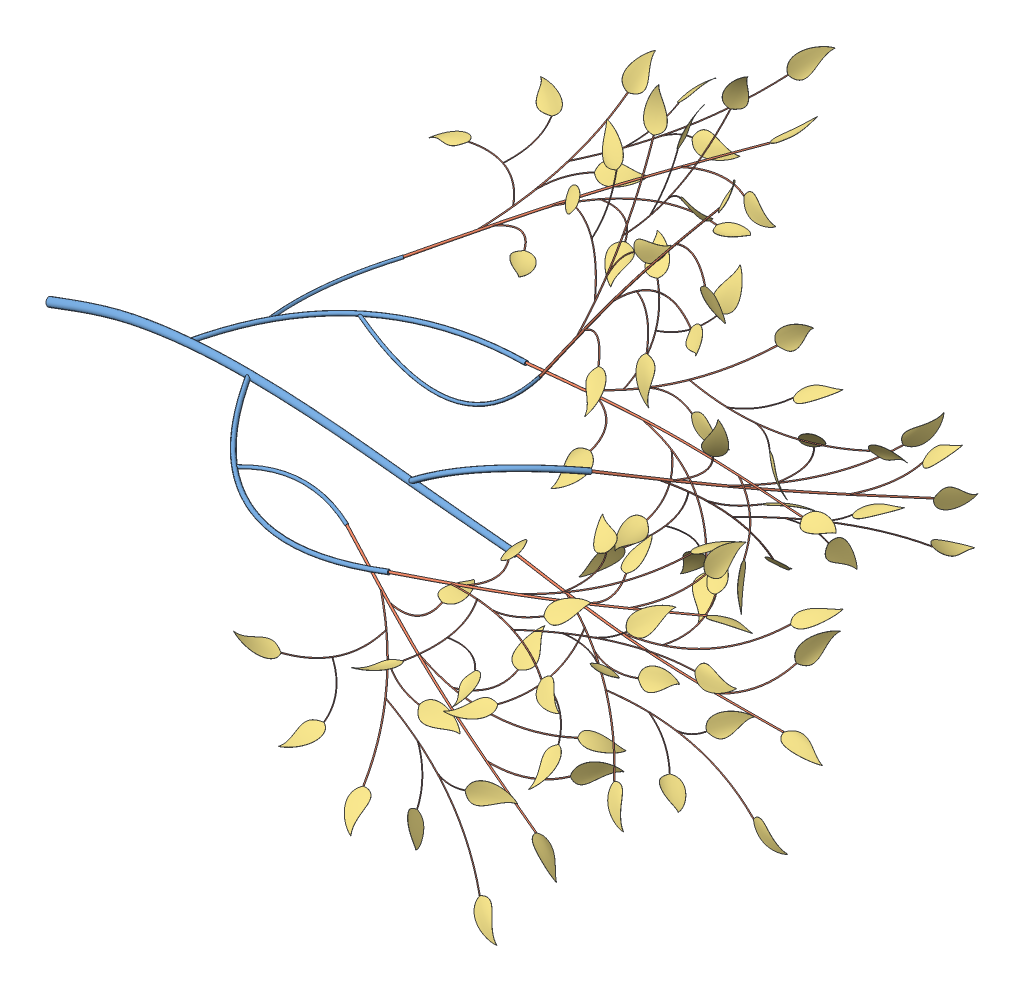
SolidWorks assembly Medium Branch, configuration Default. Lengths in mm.
Overall size (1047.38 776.48 982.97).
99 component instances, 3 part files, 14 mates.
Components (placement in the parent):
- Medium Branch-1: Medium Branch [Default] at origin size (606.89 129.86 395)
- Small Branch-1: Small Branch [Default] at (234.8483 58.1429 -218.8325) x (0.850592 -0.059738 0.522421) z (-0.522421 -0.208881 0.826707) size (314.27 42.14 439.71)
  - Small Branch-1: Small Branch [Default] at origin size (214.34 2.87 387.61)
  - Leaf-1: Leaf [Default] at (-126.8501 0 -93.2963) x (-0.636908 -0.142761 -0.757607) z (0.709104 0.277141 -0.648355) size (26.78 6 52.05)
  - Leaf-2: Leaf [Default] at (-126.8501 0 -172.3953) x (-0.013277 -0.285636 -0.958246) z (0.991939 -0.124542 0.02338) size (26.78 6 52.05)
  - Leaf-3: Leaf [Default] at (-126.8501 0 -245.0718) x (-0.525154 0.599129 0.604365) z (0.614609 -0.22419 0.756303) size (26.78 6 52.05)
  - Leaf-4: Leaf [Default] at (-92.3172 0 -285.5855) x (0.533069 0.650396 -0.54113) z (0.556089 0.212694 0.803447) size (26.78 6 52.05)
  - Leaf-5: Leaf [Default] at (-84.2583 0 -387.3824) x (-0.420387 0.890967 0.171619) z (0.131866 -0.127143 0.98308) size (26.78 6 52.05)
  - Leaf-6: Leaf [Default] at (-40.2332 0 -285.5855) x (0.372303 -0.768109 0.520961) z (-0.655996 0.179296 0.73316) size (26.78 6 52.05)
  - Leaf-7: Leaf [Default] at (-34.0505 0 -190.6428) x (0.783569 -0.523086 0.335262) z (-0.242974 0.238646 0.940219) size (26.78 6 52.05)
  - Leaf-8: Leaf [Default] at (-0.8972 0 -350) x (-0.8697 -0.488533 -0.070406) z (0.058885 -0.244321 0.967905) size (26.78 6 52.05)
  - Leaf-9: Leaf [Default] at (59.3764 0 -310.8062) x (0.063601 -0.898301 0.434754) z (-0.913477 0.123031 0.387844) size (26.78 6 52.05)
  - Leaf-10: Leaf [Default] at (86.7887 0 -277.9973) x (-0.409978 -0.23426 -0.881499) z (-0.842796 -0.272218 0.46432) size (26.78 6 52.05)
  - Leaf-11: Leaf [Default] at (71.4865 0 -194.3436) x (-0.415399 0.323221 0.850278) z (-0.822836 0.264979 -0.50272) size (26.78 6 52.05)
  - Leaf-12: Leaf [Default] at (41.4889 0 -105.4654) x (0.385119 -0.368279 -0.8462) z (-0.916478 -0.260329 -0.303804) size (26.78 6 52.05)
- Small Branch-2: Small Branch [Default] at (421.3694 47.2127 -190.7732) x (0.008005 -0.804807 0.593482) z (-0.999909 0 0.013487) size (314.27 42.14 439.71)
  - Small Branch-1: Small Branch [Default] at origin size (214.34 2.87 387.61)
  - Leaf-1: Leaf [Default] at (-126.8501 0 -93.2963) x (-0.636908 -0.142761 -0.757607) z (0.709104 0.277141 -0.648355) size (26.78 6 52.05)
  - Leaf-2: Leaf [Default] at (-126.8501 0 -172.3953) x (-0.013277 -0.285636 -0.958246) z (0.991939 -0.124542 0.02338) size (26.78 6 52.05)
  - Leaf-3: Leaf [Default] at (-126.8501 0 -245.0718) x (-0.525154 0.599129 0.604365) z (0.614609 -0.22419 0.756303) size (26.78 6 52.05)
  - Leaf-4: Leaf [Default] at (-92.3172 0 -285.5855) x (0.533069 0.650396 -0.54113) z (0.556089 0.212694 0.803447) size (26.78 6 52.05)
  - Leaf-5: Leaf [Default] at (-84.2583 0 -387.3824) x (-0.420387 0.890967 0.171619) z (0.131866 -0.127143 0.98308) size (26.78 6 52.05)
  - Leaf-6: Leaf [Default] at (-40.2332 0 -285.5855) x (0.372303 -0.768109 0.520961) z (-0.655996 0.179296 0.73316) size (26.78 6 52.05)
  - Leaf-7: Leaf [Default] at (-34.0505 0 -190.6428) x (0.783569 -0.523086 0.335262) z (-0.242974 0.238646 0.940219) size (26.78 6 52.05)
  - Leaf-8: Leaf [Default] at (-0.8972 0 -350) x (-0.8697 -0.488533 -0.070406) z (0.058885 -0.244321 0.967905) size (26.78 6 52.05)
  - Leaf-9: Leaf [Default] at (59.3764 0 -310.8062) x (0.063601 -0.898301 0.434754) z (-0.913477 0.123031 0.387844) size (26.78 6 52.05)
  - Leaf-10: Leaf [Default] at (86.7887 0 -277.9973) x (-0.409978 -0.23426 -0.881499) z (-0.842796 -0.272218 0.46432) size (26.78 6 52.05)
  - Leaf-11: Leaf [Default] at (71.4865 0 -194.3436) x (-0.415399 0.323221 0.850278) z (-0.822836 0.264979 -0.50272) size (26.78 6 52.05)
  - Leaf-12: Leaf [Default] at (41.4889 0 -105.4654) x (0.385119 -0.368279 -0.8462) z (-0.916478 -0.260329 -0.303804) size (26.78 6 52.05)
- Small Branch-3: Small Branch [Default] at (521.8164 123.8657 -108.6707) x (0.683067 -0.468153 0.560582) z (-0.597406 -0.799683 0.060107) size (314.27 42.14 439.71)
  - Small Branch-1: Small Branch [Default] at origin size (214.34 2.87 387.61)
  - Leaf-1: Leaf [Default] at (-126.8501 0 -93.2963) x (-0.636908 -0.142761 -0.757607) z (0.709104 0.277141 -0.648355) size (26.78 6 52.05)
  - Leaf-2: Leaf [Default] at (-126.8501 0 -172.3953) x (-0.013277 -0.285636 -0.958246) z (0.991939 -0.124542 0.02338) size (26.78 6 52.05)
  - Leaf-3: Leaf [Default] at (-126.8501 0 -245.0718) x (-0.525154 0.599129 0.604365) z (0.614609 -0.22419 0.756303) size (26.78 6 52.05)
  - Leaf-4: Leaf [Default] at (-92.3172 0 -285.5855) x (0.533069 0.650396 -0.54113) z (0.556089 0.212694 0.803447) size (26.78 6 52.05)
  - Leaf-5: Leaf [Default] at (-84.2583 0 -387.3824) x (-0.420387 0.890967 0.171619) z (0.131866 -0.127143 0.98308) size (26.78 6 52.05)
  - Leaf-6: Leaf [Default] at (-40.2332 0 -285.5855) x (0.372303 -0.768109 0.520961) z (-0.655996 0.179296 0.73316) size (26.78 6 52.05)
  - Leaf-7: Leaf [Default] at (-34.0505 0 -190.6428) x (0.783569 -0.523086 0.335262) z (-0.242974 0.238646 0.940219) size (26.78 6 52.05)
  - Leaf-8: Leaf [Default] at (-0.8972 0 -350) x (-0.8697 -0.488533 -0.070406) z (0.058885 -0.244321 0.967905) size (26.78 6 52.05)
  - Leaf-9: Leaf [Default] at (59.3764 0 -310.8062) x (0.063601 -0.898301 0.434754) z (-0.913477 0.123031 0.387844) size (26.78 6 52.05)
  - Leaf-10: Leaf [Default] at (86.7887 0 -277.9973) x (-0.409978 -0.23426 -0.881499) z (-0.842796 -0.272218 0.46432) size (26.78 6 52.05)
  - Leaf-11: Leaf [Default] at (71.4865 0 -194.3436) x (-0.415399 0.323221 0.850278) z (-0.822836 0.264979 -0.50272) size (26.78 6 52.05)
  - Leaf-12: Leaf [Default] at (41.4889 0 -105.4654) x (0.385119 -0.368279 -0.8462) z (-0.916478 -0.260329 -0.303804) size (26.78 6 52.05)
- Small Branch-4: Small Branch [Default] at (601.2333 65.1322 -93.4934) x (0.532435 0.844514 -0.05753) z (-0.403263 0.312824 0.859954) size (314.27 42.14 439.71)
  - Small Branch-1: Small Branch [Default] at origin size (214.34 2.87 387.61)
  - Leaf-1: Leaf [Default] at (-126.8501 0 -93.2963) x (-0.636908 -0.142761 -0.757607) z (0.709104 0.277141 -0.648355) size (26.78 6 52.05)
  - Leaf-2: Leaf [Default] at (-126.8501 0 -172.3953) x (-0.013277 -0.285636 -0.958246) z (0.991939 -0.124542 0.02338) size (26.78 6 52.05)
  - Leaf-3: Leaf [Default] at (-126.8501 0 -245.0718) x (-0.525154 0.599129 0.604365) z (0.614609 -0.22419 0.756303) size (26.78 6 52.05)
  - Leaf-4: Leaf [Default] at (-92.3172 0 -285.5855) x (0.533069 0.650396 -0.54113) z (0.556089 0.212694 0.803447) size (26.78 6 52.05)
  - Leaf-5: Leaf [Default] at (-84.2583 0 -387.3824) x (-0.420387 0.890967 0.171619) z (0.131866 -0.127143 0.98308) size (26.78 6 52.05)
  - Leaf-6: Leaf [Default] at (-40.2332 0 -285.5855) x (0.372303 -0.768109 0.520961) z (-0.655996 0.179296 0.73316) size (26.78 6 52.05)
  - Leaf-7: Leaf [Default] at (-34.0505 0 -190.6428) x (0.783569 -0.523086 0.335262) z (-0.242974 0.238646 0.940219) size (26.78 6 52.05)
  - Leaf-8: Leaf [Default] at (-0.8972 0 -350) x (-0.8697 -0.488533 -0.070406) z (0.058885 -0.244321 0.967905) size (26.78 6 52.05)
  - Leaf-9: Leaf [Default] at (59.3764 0 -310.8062) x (0.063601 -0.898301 0.434754) z (-0.913477 0.123031 0.387844) size (26.78 6 52.05)
  - Leaf-10: Leaf [Default] at (86.7887 0 -277.9973) x (-0.409978 -0.23426 -0.881499) z (-0.842796 -0.272218 0.46432) size (26.78 6 52.05)
  - Leaf-11: Leaf [Default] at (71.4865 0 -194.3436) x (-0.415399 0.323221 0.850278) z (-0.822836 0.264979 -0.50272) size (26.78 6 52.05)
  - Leaf-12: Leaf [Default] at (41.4889 0 -105.4654) x (0.385119 -0.368279 -0.8462) z (-0.916478 -0.260329 -0.303804) size (26.78 6 52.05)
- Small Branch-5: Small Branch [Default] at (599.6756 19.6986 1.0621) x (0.039468 0.490905 -0.870319) z (-0.998014 0.062159 -0.010198) size (314.27 42.14 439.71)
  - Small Branch-1: Small Branch [Default] at origin size (214.34 2.87 387.61)
  - Leaf-1: Leaf [Default] at (-126.8501 0 -93.2963) x (-0.636908 -0.142761 -0.757607) z (0.709104 0.277141 -0.648355) size (26.78 6 52.05)
  - Leaf-2: Leaf [Default] at (-126.8501 0 -172.3953) x (-0.013277 -0.285636 -0.958246) z (0.991939 -0.124542 0.02338) size (26.78 6 52.05)
  - Leaf-3: Leaf [Default] at (-126.8501 0 -245.0718) x (-0.525154 0.599129 0.604365) z (0.614609 -0.22419 0.756303) size (26.78 6 52.05)
  - Leaf-4: Leaf [Default] at (-92.3172 0 -285.5855) x (0.533069 0.650396 -0.54113) z (0.556089 0.212694 0.803447) size (26.78 6 52.05)
  - Leaf-5: Leaf [Default] at (-84.2583 0 -387.3824) x (-0.420387 0.890967 0.171619) z (0.131866 -0.127143 0.98308) size (26.78 6 52.05)
  - Leaf-6: Leaf [Default] at (-40.2332 0 -285.5855) x (0.372303 -0.768109 0.520961) z (-0.655996 0.179296 0.73316) size (26.78 6 52.05)
  - Leaf-7: Leaf [Default] at (-34.0505 0 -190.6428) x (0.783569 -0.523086 0.335262) z (-0.242974 0.238646 0.940219) size (26.78 6 52.05)
  - Leaf-8: Leaf [Default] at (-0.8972 0 -350) x (-0.8697 -0.488533 -0.070406) z (0.058885 -0.244321 0.967905) size (26.78 6 52.05)
  - Leaf-9: Leaf [Default] at (59.3764 0 -310.8062) x (0.063601 -0.898301 0.434754) z (-0.913477 0.123031 0.387844) size (26.78 6 52.05)
  - Leaf-10: Leaf [Default] at (86.7887 0 -277.9973) x (-0.409978 -0.23426 -0.881499) z (-0.842796 -0.272218 0.46432) size (26.78 6 52.05)
  - Leaf-11: Leaf [Default] at (71.4865 0 -194.3436) x (-0.415399 0.323221 0.850278) z (-0.822836 0.264979 -0.50272) size (26.78 6 52.05)
  - Leaf-12: Leaf [Default] at (41.4889 0 -105.4654) x (0.385119 -0.368279 -0.8462) z (-0.916478 -0.260329 -0.303804) size (26.78 6 52.05)
- Small Branch-6: Small Branch [Default] at (597.4823 78.5972 161.8456) x (-0.245743 0.072398 -0.966628) z (-0.948356 -0.224304 0.224298) size (314.27 42.14 439.71)
  - Small Branch-1: Small Branch [Default] at origin size (214.34 2.87 387.61)
  - Leaf-1: Leaf [Default] at (-126.8501 0 -93.2963) x (-0.636908 -0.142761 -0.757607) z (0.709104 0.277141 -0.648355) size (26.78 6 52.05)
  - Leaf-2: Leaf [Default] at (-126.8501 0 -172.3953) x (-0.013277 -0.285636 -0.958246) z (0.991939 -0.124542 0.02338) size (26.78 6 52.05)
  - Leaf-3: Leaf [Default] at (-126.8501 0 -245.0718) x (-0.525154 0.599129 0.604365) z (0.614609 -0.22419 0.756303) size (26.78 6 52.05)
  - Leaf-4: Leaf [Default] at (-92.3172 0 -285.5855) x (0.533069 0.650396 -0.54113) z (0.556089 0.212694 0.803447) size (26.78 6 52.05)
  - Leaf-5: Leaf [Default] at (-84.2583 0 -387.3824) x (-0.420387 0.890967 0.171619) z (0.131866 -0.127143 0.98308) size (26.78 6 52.05)
  - Leaf-6: Leaf [Default] at (-40.2332 0 -285.5855) x (0.372303 -0.768109 0.520961) z (-0.655996 0.179296 0.73316) size (26.78 6 52.05)
  - Leaf-7: Leaf [Default] at (-34.0505 0 -190.6428) x (0.783569 -0.523086 0.335262) z (-0.242974 0.238646 0.940219) size (26.78 6 52.05)
  - Leaf-8: Leaf [Default] at (-0.8972 0 -350) x (-0.8697 -0.488533 -0.070406) z (0.058885 -0.244321 0.967905) size (26.78 6 52.05)
  - Leaf-9: Leaf [Default] at (59.3764 0 -310.8062) x (0.063601 -0.898301 0.434754) z (-0.913477 0.123031 0.387844) size (26.78 6 52.05)
  - Leaf-10: Leaf [Default] at (86.7887 0 -277.9973) x (-0.409978 -0.23426 -0.881499) z (-0.842796 -0.272218 0.46432) size (26.78 6 52.05)
  - Leaf-11: Leaf [Default] at (71.4865 0 -194.3436) x (-0.415399 0.323221 0.850278) z (-0.822836 0.264979 -0.50272) size (26.78 6 52.05)
  - Leaf-12: Leaf [Default] at (41.4889 0 -105.4654) x (0.385119 -0.368279 -0.8462) z (-0.916478 -0.260329 -0.303804) size (26.78 6 52.05)
- Small Branch-7: Small Branch [Default] at (462.6137 23.3972 81.3505) x (0.203661 0.015322 -0.978922) z (-0.872913 0.455611 -0.174475) size (314.27 42.14 439.71)
  - Small Branch-1: Small Branch [Default] at origin size (214.34 2.87 387.61)
  - Leaf-1: Leaf [Default] at (-126.8501 0 -93.2963) x (-0.636908 -0.142761 -0.757607) z (0.709104 0.277141 -0.648355) size (26.78 6 52.05)
  - Leaf-2: Leaf [Default] at (-126.8501 0 -172.3953) x (-0.013277 -0.285636 -0.958246) z (0.991939 -0.124542 0.02338) size (26.78 6 52.05)
  - Leaf-3: Leaf [Default] at (-126.8501 0 -245.0718) x (-0.525154 0.599129 0.604365) z (0.614609 -0.22419 0.756303) size (26.78 6 52.05)
  - Leaf-4: Leaf [Default] at (-92.3172 0 -285.5855) x (0.533069 0.650396 -0.54113) z (0.556089 0.212694 0.803447) size (26.78 6 52.05)
  - Leaf-5: Leaf [Default] at (-84.2583 0 -387.3824) x (-0.420387 0.890967 0.171619) z (0.131866 -0.127143 0.98308) size (26.78 6 52.05)
  - Leaf-6: Leaf [Default] at (-40.2332 0 -285.5855) x (0.372303 -0.768109 0.520961) z (-0.655996 0.179296 0.73316) size (26.78 6 52.05)
  - Leaf-7: Leaf [Default] at (-34.0505 0 -190.6428) x (0.783569 -0.523086 0.335262) z (-0.242974 0.238646 0.940219) size (26.78 6 52.05)
  - Leaf-8: Leaf [Default] at (-0.8972 0 -350) x (-0.8697 -0.488533 -0.070406) z (0.058885 -0.244321 0.967905) size (26.78 6 52.05)
  - Leaf-9: Leaf [Default] at (59.3764 0 -310.8062) x (0.063601 -0.898301 0.434754) z (-0.913477 0.123031 0.387844) size (26.78 6 52.05)
  - Leaf-10: Leaf [Default] at (86.7887 0 -277.9973) x (-0.409978 -0.23426 -0.881499) z (-0.842796 -0.272218 0.46432) size (26.78 6 52.05)
  - Leaf-11: Leaf [Default] at (71.4865 0 -194.3436) x (-0.415399 0.323221 0.850278) z (-0.822836 0.264979 -0.50272) size (26.78 6 52.05)
  - Leaf-12: Leaf [Default] at (41.4889 0 -105.4654) x (0.385119 -0.368279 -0.8462) z (-0.916478 -0.260329 -0.303804) size (26.78 6 52.05)
Mates (geometry in assembly coordinates):
- Coincident2: coincident: point of Medium Branch-1; point of Small Branch-1/Small Branch-1
- Coincident3: coincident anti-aligned: plane of Medium Branch-1 through (233.3995 58.7503 -219.5946) normal (0.522421 0.208881 -0.826707); circle of Small Branch-1/Small Branch-1
- Coincident4: coincident: point of Medium Branch-1; point of Small Branch-2/Small Branch-1
- Coincident5: coincident anti-aligned: plane of Medium Branch-1 through (421.3644 44.5042 -191.1426) normal (0.999909 0 -0.013487); circle of Small Branch-2/Small Branch-1
- Coincident6: coincident: point of Medium Branch-1; point of Small Branch-3/Small Branch-1
- Coincident7: coincident anti-aligned: plane of Medium Branch-1 through (523.2357 122.8607 -107.9338) normal (0.597406 0.799683 -0.060107); circle of Small Branch-3/Small Branch-1
- Coincident8: coincident: point of Medium Branch-1; point of Small Branch-4/Small Branch-1
- Coincident9: coincident anti-aligned: plane of Medium Branch-1 through (598.1271 64.6248 -94.7654) normal (0.403263 -0.312824 -0.859954); circle of Small Branch-4/Small Branch-1
- Coincident10: coincident: point of Medium Branch-1; point of Small Branch-5/Small Branch-1
- Coincident11: coincident anti-aligned: plane of Medium Branch-1 through (599.7307 19.9815 -2.6059) normal (0.998014 -0.062159 0.010198); circle of Small Branch-5/Small Branch-1
- Coincident12: coincident: point of Medium Branch-1; point of Small Branch-6/Small Branch-1
- Coincident13: coincident anti-aligned: plane of Medium Branch-1 through (596.9249 78.4705 159.3621) normal (0.948356 0.224304 -0.224298); circle of Small Branch-6/Small Branch-1
- Coincident14: coincident: point of Medium Branch-1; point of Small Branch-7/Small Branch-1
- Coincident15: coincident anti-aligned: plane of Medium Branch-1 through (462.956 23.3262 79.453) normal (0.872913 -0.455611 0.174475); circle of Small Branch-7/Small Branch-1
